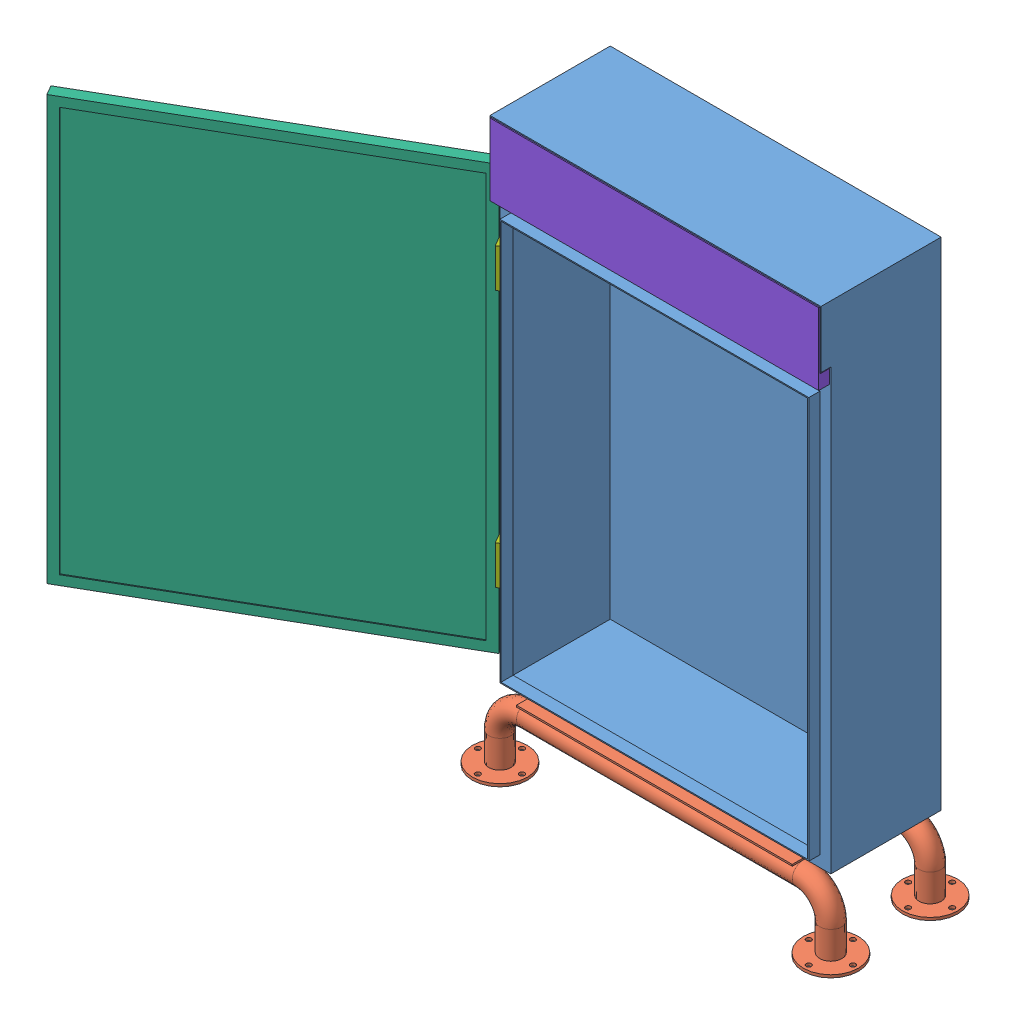
SolidWorks assembly full tu dien, configuration Default. Lengths in mm.
Overall size (1226.57 1028 484.81).
12 component instances, 8 part files, 33 mates.
Components (placement in the parent):
- tu dien-1: tu dien [Default] at (87.3317 434.2752 846.0635) size (600 900 220)
- chan tu-1: chan tu [Default] at (87.3317 -38.7248 866.0635) size (700 128 280)
- 8020-2134 Hinge Door Configuration-$PARTNUMBER_Latch-1: 8020-2134 Hinge Door Configuration-$PARTNUMBER_Latch [Default] at (-269.4127 621.0967 1021.9084) x (0 -1 0) z (0.5 0 0.866025) size (69.85 13.46 17.07)
- 8020-2134 Hinge Door Configuration-$PARTNUMBER_Latch Plate-1: 8020-2134 Hinge Door Configuration-$PARTNUMBER_Latch Plate [Default] at (-212.6683 582.4252 1052.5861) x (0 1 0) z (-1 0 0) size (101.6 38.1 4.78)
- 8020-2134 Hinge Door Configuration-$PARTNUMBER_Striker-1: 8020-2134 Hinge Door Configuration-$PARTNUMBER_Striker [Default] at (-192.0435 582.4252 1001.2273) x (0 1 0) z (0 0 1) size (41.91 17.22 10.67)
- cua tu-1: cua tu [Default] at (-529.4289 368.2752 1133.5487) x (0.866025 0 -0.5) z (0.5 0 0.866025) size (600 768 20)
- 8020-2134 Hinge Door Configuration-$PARTNUMBER_Strike Plate-2: 8020-2134 Hinge Door Configuration-$PARTNUMBER_Strike Plate [Default] at (-263.2713 582.9967 994.5472) x (0 1 0) z (0.866025 0 -0.5) size (70.21 38.1 22.94)
- 8020-2134 Hinge Door Configuration-$PARTNUMBER_Latch Plate-2: 8020-2134 Hinge Door Configuration-$PARTNUMBER_Latch Plate [Default] at (-212.6683 116.0252 1052.5861) x (0 1 0) z (-1 0 0) size (101.6 38.1 4.78)
- 8020-2134 Hinge Door Configuration-$PARTNUMBER_Strike Plate-3: 8020-2134 Hinge Door Configuration-$PARTNUMBER_Strike Plate [Default] at (-263.2713 116.5967 994.5472) x (0 1 0) z (0.866025 0 -0.5) size (70.21 38.1 22.94)
- 8020-2134 Hinge Door Configuration-$PARTNUMBER_Latch-2: 8020-2134 Hinge Door Configuration-$PARTNUMBER_Latch [Default] at (-269.4127 154.6967 1021.9084) x (0 -1 0) z (0.5 0 0.866025) size (69.85 13.46 17.07)
- 8020-2134 Hinge Door Configuration-$PARTNUMBER_Striker-2: 8020-2134 Hinge Door Configuration-$PARTNUMBER_Striker [Default] at (-192.0435 116.0252 1001.2273) x (0 1 0) z (0 0 1) size (41.91 17.22 10.67)
- ngan keo-1: ngan keo [Default] at (87.3317 844.7752 886.0635) size (596 130 180)
Mates (geometry in assembly coordinates):
- Coincident1: coincident anti-aligned: plane of tu dien-1 through (387.3317 -15.7248 1046.0635) normal (0 -1 0); plane of chan tu-1 through (87.3317 -15.7248 866.0635) normal (0 1 0)
- Distance1: distance = 20 mm aligned: plane of tu dien-1 through (87.3317 434.2752 1046.0635) normal (0 0 1); plane of chan tu-1 through (-162.6683 -15.7248 1066.0635) normal (0 0 1)
- Distance2: distance = 50 mm aligned: plane of chan tu-1 through (337.3317 -15.7248 846.0635) normal (1 0 0); plane of tu dien-1 through (387.3317 -15.7248 1046.0635) normal (1 0 0)
- Coincident4: coincident anti-aligned: plane of 8020-2134 Hinge Door Configuration-$PARTNUMBER_Latch Plate-1 through (-217.4435 652.2752 986.0635) normal (-1 0 0); plane of 8020-2134 Hinge Door Configuration-$PARTNUMBER_Striker-1 through (-217.4435 622.4429 1012.0731) normal (1 0 0)
- Concentric1: concentric anti-aligned: cylinder of 8020-2134 Hinge Door Configuration-$PARTNUMBER_Latch Plate-1 through (-212.6683 616.4866 1017.4071) axis (-1 0 0) radius 2.032; cone of 8020-2134 Hinge Door Configuration-$PARTNUMBER_Striker-1 through (-220.4915 616.4866 1017.4071) axis (1 0 0)
- Concentric2: concentric anti-aligned: cylinder of 8020-2134 Hinge Door Configuration-$PARTNUMBER_Latch Plate-1 through (-212.6683 586.4892 1017.4071) axis (-1 0 0) radius 2.032; cone of 8020-2134 Hinge Door Configuration-$PARTNUMBER_Striker-1 through (-220.4915 586.4892 1017.4071) axis (1 0 0)
- Concentric4: concentric aligned: cylinder of 8020-2134 Hinge Door Configuration-$PARTNUMBER_Latch-1 through (-231.3903 577.4595 1017.4071) axis (0 -1 0) radius 5.0546; cylinder of 8020-2134 Hinge Door Configuration-$PARTNUMBER_Striker-1 through (-231.3903 25982.4252 1017.4071) axis (0 -1 0) radius 1.2495
- Tangent1: tangent anti-aligned: plane of 8020-2134 Hinge Door Configuration-$PARTNUMBER_Latch-1 through (-231.9618 596.0269 1016.4173) normal (0 1 0); cylinder of 8020-2134 Hinge Door Configuration-$PARTNUMBER_Striker-1 through (-230.696 599.9956 1012.0731) axis (0 0 1) radius 3.9688
- Coincident6: coincident aligned: plane of tu dien-1 through (387.3317 -15.7248 1046.0635) normal (0 -1 0); plane of cua tu-1 through (-259.6213 -15.7248 1000.8692) normal (0 -1 0)
- Coincident7: coincident anti-aligned: plane of tu dien-1 through (-212.6683 -15.7248 1046.0635) normal (-1 0 0); plane of 8020-2134 Hinge Door Configuration-$PARTNUMBER_Latch Plate-1 through (-212.6683 601.4752 1005.1135) normal (1 0 0)
- Concentric7: concentric anti-aligned: cylinder of 8020-2134 Hinge Door Configuration-$PARTNUMBER_Latch-1 through (-236.5592 632.0441 1008.4543) axis (0.5 0 0.866025) radius 2.1082; cylinder of 8020-2134 Hinge Door Configuration-$PARTNUMBER_Strike Plate-2 through (-236.5592 632.0441 1008.4543) axis (-0.5 0 -0.866025) radius 2.032
- Coincident12: coincident anti-aligned: plane of 8020-2134 Hinge Door Configuration-$PARTNUMBER_Latch-1 through (-230.73 636.9717 1005.0888) normal (-0.5 0 -0.866025); plane of 8020-2134 Hinge Door Configuration-$PARTNUMBER_Strike Plate-2 through (-230.708 566.9439 1005.0761) normal (0.5 0 0.866025)
- Concentric8: concentric anti-aligned: cylinder of 8020-2134 Hinge Door Configuration-$PARTNUMBER_Latch-1 through (-236.5592 572.0493 1008.4543) axis (0.5 0 0.866025) radius 2.1082; cylinder of 8020-2134 Hinge Door Configuration-$PARTNUMBER_Strike Plate-2 through (-236.5592 572.0493 1008.4543) axis (-0.5 0 -0.866025) radius 2.032
- Coincident13: coincident anti-aligned: plane of cua tu-1 through (-259.6213 -15.7248 1000.8692) normal (0.866025 0 -0.5); plane of 8020-2134 Hinge Door Configuration-$PARTNUMBER_Strike Plate-2 through (-250.5713 566.9439 1016.5442) normal (-0.866025 0 0.5)
- LimitAngle1: limit planar angle = 2.617994 rad anti-aligned: plane of tu dien-1 through (87.3317 434.2752 1046.0635) normal (0 0 1); plane of cua tu-1 through (-519.4289 368.2752 1150.8692) normal (0.5 0 0.866025)
- Distance4: distance = 100 mm aligned: plane of 8020-2134 Hinge Door Configuration-$PARTNUMBER_Latch Plate-1 through (-212.6683 652.2752 986.0635) normal (0 1 0); plane of cua tu-1 through (-259.6213 752.2752 1000.8692) normal (0 1 0)
- Coincident18: coincident anti-aligned: plane of 8020-2134 Hinge Door Configuration-$PARTNUMBER_Latch Plate-2 through (-217.4435 185.8752 986.0635) normal (-1 0 0); plane of 8020-2134 Hinge Door Configuration-$PARTNUMBER_Striker-2 through (-217.4435 156.0429 1012.0731) normal (1 0 0)
- Concentric9: concentric anti-aligned: cylinder of 8020-2134 Hinge Door Configuration-$PARTNUMBER_Latch Plate-2 through (-212.6683 150.0866 1017.4071) axis (-1 0 0) radius 2.032; cone of 8020-2134 Hinge Door Configuration-$PARTNUMBER_Striker-2 through (-220.4915 150.0866 1017.4071) axis (1 0 0)
- Concentric10: concentric anti-aligned: cylinder of 8020-2134 Hinge Door Configuration-$PARTNUMBER_Latch Plate-2 through (-212.6683 120.0892 1017.4071) axis (-1 0 0) radius 2.032; cone of 8020-2134 Hinge Door Configuration-$PARTNUMBER_Striker-2 through (-220.4915 120.0892 1017.4071) axis (1 0 0)
- Concentric11: concentric aligned: cylinder of 8020-2134 Hinge Door Configuration-$PARTNUMBER_Latch-2 through (-231.3903 111.0595 1017.4071) axis (0 -1 0) radius 5.0546; cylinder of 8020-2134 Hinge Door Configuration-$PARTNUMBER_Striker-2 through (-231.3903 25516.0252 1017.4071) axis (0 -1 0) radius 1.2495
- Coincident19: coincident anti-aligned: plane of tu dien-1 through (-212.6683 -15.7248 1046.0635) normal (-1 0 0); plane of 8020-2134 Hinge Door Configuration-$PARTNUMBER_Latch Plate-2 through (-212.6683 135.0752 1005.1135) normal (1 0 0)
- Concentric12: concentric anti-aligned: cylinder of 8020-2134 Hinge Door Configuration-$PARTNUMBER_Strike Plate-3 through (-236.5592 165.6441 1008.4543) axis (-0.5 0 -0.866025) radius 2.032; cylinder of 8020-2134 Hinge Door Configuration-$PARTNUMBER_Latch-2 through (-236.5592 165.6441 1008.4543) axis (0.5 0 0.866025) radius 2.1082
- Concentric13: concentric aligned: cylinder of 8020-2134 Hinge Door Configuration-$PARTNUMBER_Strike Plate-3 through (-236.5592 105.6493 1008.4543) axis (-0.5 0 -0.866025) radius 2.032; cone of 8020-2134 Hinge Door Configuration-$PARTNUMBER_Latch-2 through (-234.5018 105.6493 1012.0179) axis (-0.5 0 -0.866025)
- Coincident21: coincident anti-aligned: plane of 8020-2134 Hinge Door Configuration-$PARTNUMBER_Strike Plate-3 through (-230.708 100.5439 1005.0761) normal (0.5 0 0.866025); plane of 8020-2134 Hinge Door Configuration-$PARTNUMBER_Latch-2 through (-230.73 170.5717 1005.0888) normal (-0.5 0 -0.866025)
- Coincident22: coincident anti-aligned: plane of cua tu-1 through (-259.6213 -15.7248 1000.8692) normal (0.866025 0 -0.5); plane of 8020-2134 Hinge Door Configuration-$PARTNUMBER_Strike Plate-3 through (-250.5713 100.5439 1016.5442) normal (-0.866025 0 0.5)
- Distance5: distance = 100 mm aligned: plane of 8020-2134 Hinge Door Configuration-$PARTNUMBER_Latch Plate-2 through (-212.6683 84.2752 1024.1635) normal (0 -1 0); plane of tu dien-1 through (387.3317 -15.7248 1046.0635) normal (0 -1 0)
- Tangent2: tangent anti-aligned: plane of 8020-2134 Hinge Door Configuration-$PARTNUMBER_Latch-2 through (-231.9618 129.6269 1016.4173) normal (0 1 0); cylinder of 8020-2134 Hinge Door Configuration-$PARTNUMBER_Striker-2 through (-230.696 133.5956 1012.0731) axis (0 0 1) radius 3.9688
- Coincident24: coincident aligned: plane of cua tu-1 through (-529.4289 368.2752 1133.5487) normal (-0.5 0 -0.866025); plane of 8020-2134 Hinge Door Configuration-$PARTNUMBER_Strike Plate-3 through (-269.6213 100.5439 983.5487) normal (-0.5 0 -0.866025)
- Coincident25: coincident aligned: plane of cua tu-1 through (-529.4289 368.2752 1133.5487) normal (-0.5 0 -0.866025); plane of 8020-2134 Hinge Door Configuration-$PARTNUMBER_Strike Plate-2 through (-269.6213 566.9439 983.5487) normal (-0.5 0 -0.866025)
- Distance6: distance = 140 mm aligned: plane of 8020-2134 Hinge Door Configuration-$PARTNUMBER_Latch Plate-1 through (-212.6683 550.6752 986.0635) normal (0 0 -1); plane of tu dien-1 through (87.3317 434.2752 846.0635) normal (0 0 -1)
- Coincident27: coincident anti-aligned: plane of tu dien-1 through (-210.6683 -15.7248 1046.0635) normal (1 0 0); plane of ngan keo-1 through (-210.6683 807.2752 1066.0635) normal (-1 0 0)
- Coincident28: coincident anti-aligned: plane of tu dien-1 through (387.3317 882.2752 1046.0635) normal (0 -1 0); plane of ngan keo-1 through (385.3317 882.2752 1066.0635) normal (0 1 0)
- LimitDistance2: limit distance = 0 mm anti-aligned: plane of ngan keo-1 through (87.3317 844.7752 1046.0635) normal (0 0 -1); plane of tu dien-1 through (87.3317 434.2752 1046.0635) normal (0 0 1)
